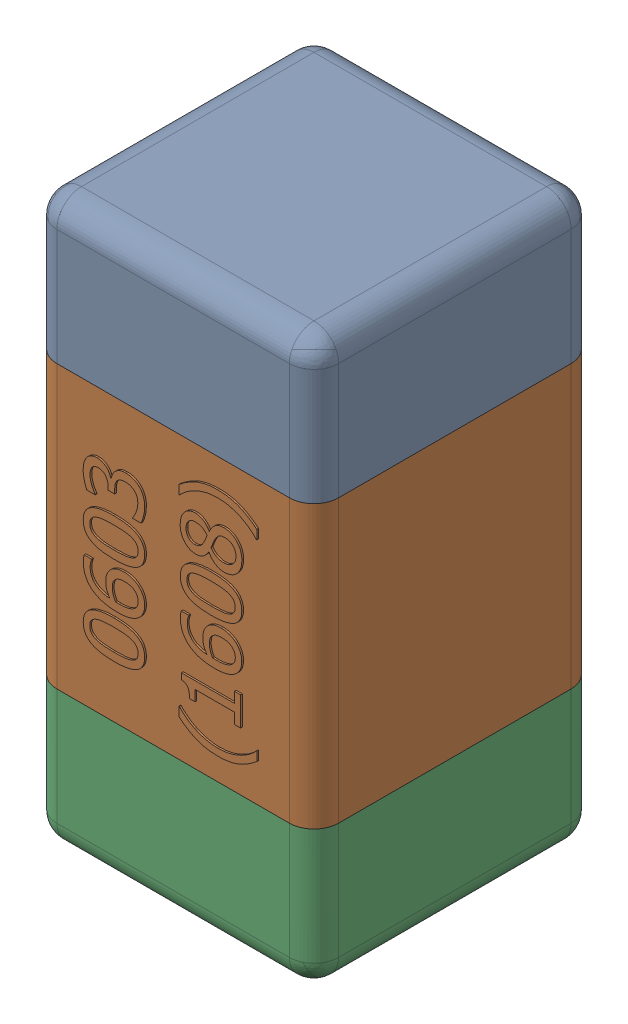
SolidWorks assembly C31, configuration Standard. Lengths in mm.
Overall size (0.81 1.61 0.81).
4 component instances, 3 part files, 0 mates.
Components (placement in the parent):
- C31-subassembly-1-1: C31-subassembly-1 [Standard] at (-9.5001 -1.4999 0) x (0 1 0) z (0 0 1) size (1.61 0.81 0.81)
  - User Library-0603_Cap-1: User Library-0603_Cap [Standard] at origin size (0.41 0.81 0.81)
  - User Library-0603_Cap-1-1: User Library-0603_Cap-1 [Standard] at origin size (0.8 0.8 0.81)
  - User Library-0603_Cap-2-1: User Library-0603_Cap-2 [Standard] at origin size (0.41 0.81 0.81)
